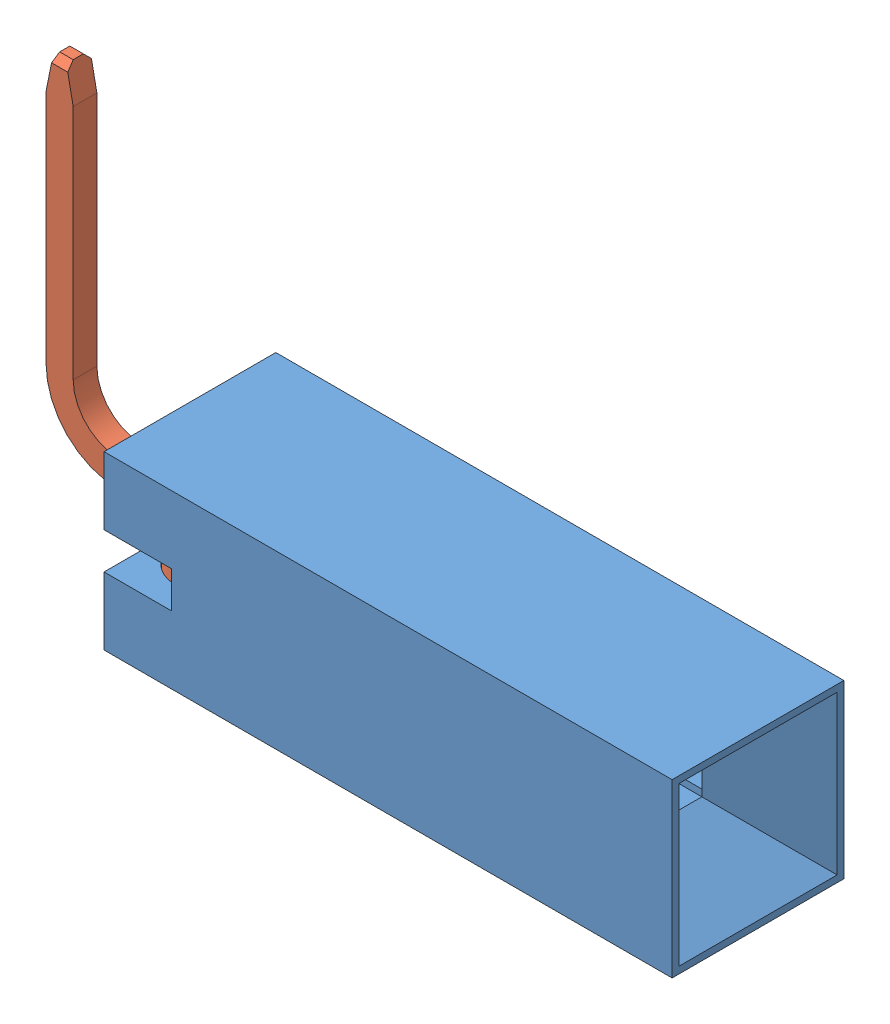
SolidWorks assembly H254_90deg_1pin, configuration Default. Lengths in mm.
Overall size (10.36 6.14 2.54).
3 component instances, 2 part files, 0 mates.
Components (placement in the parent):
- FrameAndPin_H254_90deg-1: FrameAndPin_H254_90deg [Default] at origin size (10.36 6.14 2.54)
  - frame_H254-1: frame_H254 [Default] at origin size (8.4 2.54 2.54)
  - pin-90deg-1: pin-90deg [Default] at (-0.0461 1.2682 1.27) x (0 0 -1) z (0.999998 -0.002105 0) size (1.95 5.07 7.58)
